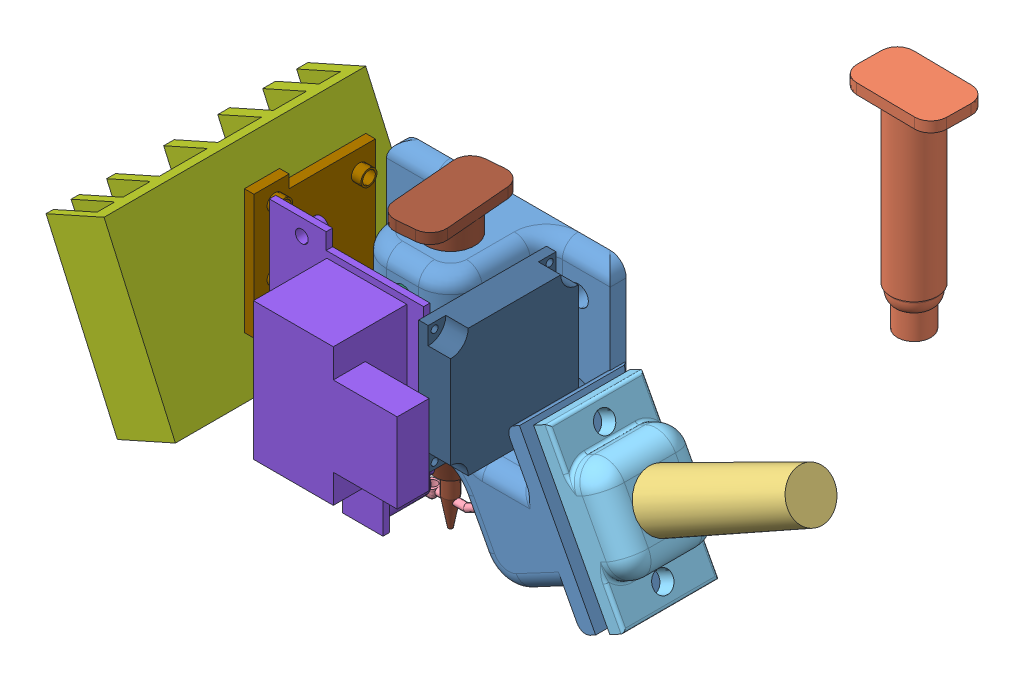
SolidWorks assembly nozzle_assembly, configuration Default. Lengths in mm.
Overall size (195.59 149.58 100.55).
12 component instances, 11 part files, 19 mates.
Components (placement in the parent):
- nozzle3_V0-1: nozzle3_V0 [Default] at (22.5056 35.4189 53.8354) size (95.46 72.96 36.02)
- syringe_model-1: syringe_model [Default] at (139.4556 151.6437 25.6693) x (-0.012868 0 0.999917) z (-0.999917 0 -0.012868) size (17.59 66.17 28.4)
- dental_tool_model-1: dental_tool_model [Default] at (69.8428 27.6487 68.8354) x (-0.038441 0.072297 0.996642) z (0.467895 -0.879983 0.081881) size (18 101.69 18)
- tip_model-1: tip_model [Default] at (50.6829 17.4611 68.8354) x (0.882948 0.469472 0) z (0 0 1) size (32.23 9.09 4.04)
- collar_V0-1: collar_V0 [Default] at (78.5262 61.033 83.8354) x (0.469472 -0.882948 0) z (0 0 1) size (50.8 15 31.1)
- 93365A140_HEAT-SET INSERTS FOR PLASTICS-1: 93365A140_HEAT-SET INSERTS FOR PLASTICS [93365A140] at (37.5056 50.0189 83.8354) x (-0.923728 -0.383049 0) z (-0.383049 0.923728 0) size (6.35 5.19 6.35)
- 93365A140_HEAT-SET INSERTS FOR PLASTICS-2: 93365A140_HEAT-SET INSERTS FOR PLASTICS [93365A140] at (37.5056 75.4189 83.8354) x (-0.923728 -0.383049 0) z (-0.383049 0.923728 0) size (6.35 5.19 6.35)
- heatsink-1: heatsink [Default] at (-22.4981 83.5542 117.2426) x (0 0 -1) z (-0.407632 0.913146 0) size (81.9 19.9 54.8)
- sensing_board-1: sensing_board [Default] at (3.766 88.9262 89.7673) x (0 -1 0) z (-1 0 0) size (73.67 39.39 63)
- heater_board-1: heater_board [Default] at (-1.5456 87.2884 53.2802) x (0 -1 0) z (-1 0 0) size (39 38 6)
- fan-1: fan [Default] at (54.109 43.0892 95.3945) x (0 0 -1) z (0 -1 0) size (40 10 40)
- syringe_OG-1: syringe_OG [Default] at (37.5056 21.0687 68.8354) x (0.996388 0 -0.084912) z (0.084912 0 0.996388) size (15.75 90.3 30.7)
Mates (geometry in assembly coordinates):
- Concentric1: concentric anti-aligned: cylinder of dental_tool_model-1 through (60.5719 22.7192 68.8354) axis (0.882948 0.469472 0) radius 2.35; cylinder of tip_model-1 through (60.5719 22.7192 68.8354) axis (-0.882948 -0.469472 0) radius 2
- Coincident1: coincident anti-aligned: plane of dental_tool_model-1 through (60.5719 22.7192 68.8354) normal (-0.882948 -0.469472 0); plane of tip_model-1 through (60.5719 22.7192 68.8354) normal (0.882948 0.469472 0)
- Concentric4: concentric anti-aligned: cone of nozzle3_V0-1 through (83.6102 34.9689 68.8354) axis (-0.882948 -0.469472 0); cone of dental_tool_model-1 through (150.3588 70.4598 68.8354) axis (0.882948 0.469472 0)
- Coincident3: coincident anti-aligned: plane of nozzle3_V0-1 through (69.8428 27.6487 68.8354) normal (0.882948 0.469472 0); plane of dental_tool_model-1 through (69.8428 27.6487 68.8354) normal (-0.882948 -0.469472 0)
- Concentric5: concentric aligned: cone of dental_tool_model-1 through (150.3588 70.4598 68.8354) axis (0.882948 0.469472 0); cone of collar_V0-1 through (103.695 45.6482 68.8354) axis (0.882948 0.469472 0)
- Concentric6: concentric aligned: cylinder of nozzle3_V0-1 through (0.4789 12.7391 68.8354) axis (0.882948 0.469472 0) radius 3.175; cylinder of collar_V0-1 through (76.9283 53.388 68.8354) axis (0.882948 0.469472 0) radius 3.175
- Distance1: distance = 5 mm anti-aligned: plane of nozzle3_V0-1 through (93.0781 23.0146 53.8354) normal (0.882948 0.469472 0); plane of collar_V0-1 through (78.5262 61.033 83.8354) normal (-0.882948 -0.469472 0)
- Concentric8: concentric anti-aligned: cone of nozzle3_V0-1 through (37.5056 75.4189 83.8354) axis (0 0 -1); cylinder of 93365A140_HEAT-SET INSERTS FOR PLASTICS-2 through (37.5056 75.4189 83.8354) axis (0 0 1) radius 2.921
- Coincident5: coincident aligned: plane of nozzle3_V0-1 through (22.5056 35.4189 83.8354) normal (0 0 1); plane of 93365A140_HEAT-SET INSERTS FOR PLASTICS-2 through (37.5056 75.4189 83.8354) normal (0 0 1)
- Concentric9: concentric anti-aligned: cone of nozzle3_V0-1 through (37.5056 50.0189 83.8354) axis (0 0 -1); cylinder of 93365A140_HEAT-SET INSERTS FOR PLASTICS-1 through (37.5056 50.0189 83.8354) axis (0 0 1) radius 2.921
- Coincident6: coincident aligned: plane of nozzle3_V0-1 through (22.5056 35.4189 83.8354) normal (0 0 1); plane of 93365A140_HEAT-SET INSERTS FOR PLASTICS-1 through (37.5056 50.0189 83.8354) normal (0 0 1)
- Parallel2: parallel anti-aligned: plane of nozzle3_V0-1 through (22.5056 35.4189 83.8354) normal (0 0 1); plane of sensing_board-1 through (3.766 88.9262 89.7673) normal (0 0 -1)
- Parallel3: parallel: line of nozzle3_V0-1 through (52.5056 80.4189 73.8354) axis (0 -1 0); plane of sensing_board-1 through (66.766 88.9262 89.7673) normal (1 0 0)
- Parallel4: parallel anti-aligned: plane of nozzle3_V0-1 through (22.5056 35.4189 83.8354) normal (-1 0 0); plane of heater_board-1 through (-1.5456 87.2884 53.2802) normal (1 0 0)
- Parallel5: parallel aligned: plane of nozzle3_V0-1 through (22.5056 85.4189 83.8354) normal (0 1 0); plane of heater_board-1 through (-4.5456 83.2884 53.2802) normal (0 1 0)
- Parallel6: parallel aligned: line of heatsink-1 through (-22.4981 83.5542 117.2426) axis (0 0 -1); line of heater_board-1 through (-4.5456 83.2884 80.2802) axis (0 0 -1)
- Parallel7: parallel anti-aligned: plane of nozzle3_V0-1 through (52.5056 35.4189 83.8354) normal (1 0 0); plane of fan-1 through (54.109 43.0892 95.3945) normal (-1 0 0)
- Parallel8: parallel aligned: plane of nozzle3_V0-1 through (22.5056 85.4189 83.8354) normal (0 1 0); plane of fan-1 through (64.109 83.0892 95.3945) normal (0 1 0)
- Concentric10: concentric anti-aligned: cylinder of nozzle3_V0-1 through (37.5056 43.4189 68.8354) axis (0 1 0) radius 7.5; cylinder of syringe_OG-1 through (37.5056 92.3687 68.8354) axis (0 -1 0) radius 7.6
